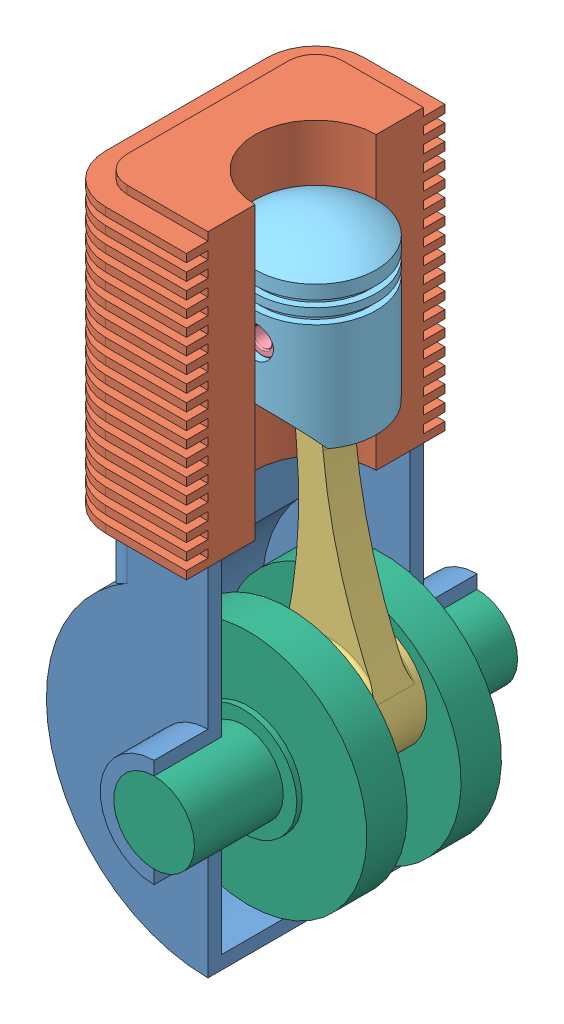
SolidWorks assembly Złożenie, configuration Default. Lengths in mm.
Overall size (122.37 241.19 120).
6 component instances, 6 part files, 12 mates.
Components (placement in the parent):
- Obudowa-1: Obudowa [Default] at (24.5213 60.7342 119.9194) size (60 132 120)
- cylinder-1: cylinder [Default] at (24.5213 132.7342 124.9194) x (0 0 -1) z (1 0 0) size (96 108 48)
- Korbowód-1: Korbowód [Default] at (35.8522 77.2148 84.9194) x (0.995532 0.094424 0) z (0 0 1) size (40 151 20)
- Sworzeń-1: Sworzeń [Default] at (24.5213 196.6787 64.9194) x (0.04525 -0.998976 0) z (0 0 1) size (12 12 40)
- Tłok-1: Tłok [60] at (24.5213 166.6787 84.9194) size (45 60 45)
- Wał-1: Wał [Default] at (24.5213 60.7342 111.9194) x (0.824032 -0.566544 0) z (0 0 1) size (88 88 120)
Mates (geometry in assembly coordinates):
- Wspólnie1: coincident anti-aligned: plane of Obudowa-1 through (-15.4787 132.7342 124.9194) normal (0 1 0); plane of cylinder-1 through (24.5213 132.7342 84.9194) normal (0 -1 0)
- Wspólnie2: coincident aligned: plane of Obudowa-1 through (24.5213 80.7342 144.9194) normal (1 0 0); plane of cylinder-1 through (24.5213 240.7342 107.4194) normal (1 0 0)
- Wspólnie3: coincident aligned: plane of Obudowa-1 through (24.5213 60.7342 44.9194) normal (0 0 -1); plane of cylinder-1 through (-15.4787 240.7342 44.9194) normal (0 0 -1)
- Koncentryczne11: concentric anti-aligned: cylinder of Sworzeń-1 through (24.5213 196.6787 104.9194) axis (0 0 -1) radius 6; cylinder of Tłok-1 through (24.5213 196.6787 62.4194) axis (0 0 1) radius 6
- Szerokość1: width anti-aligned: plane of Sworzeń-1 through (24.5213 196.6787 104.9194) normal (0 0 1); plane of Tłok-1 through (24.5213 196.6787 64.9194) normal (0 0 -1); plane of Sworzeń-1 through (24.5213 196.6787 94.9194) normal (0 0 -1); plane of Tłok-1 through (24.5213 196.6787 74.9194) normal (0 0 1)
- Koncentryczne12: concentric aligned: cylinder of Korbowód-1 through (24.5213 196.6787 94.9194) axis (0 0 -1) radius 6; cylinder of Sworzeń-1 through (24.5213 196.6787 104.9194) axis (0 0 -1) radius 6
- Wspólnie4: coincident anti-aligned: plane of Korbowód-1 through (24.5213 196.6787 94.9194) normal (0 0 1); plane of Tłok-1 through (24.5213 196.6787 94.9194) normal (0 0 -1)
- Koncentryczne13: concentric anti-aligned: cylinder of Korbowód-1 through (35.8522 77.2148 94.9194) axis (0 0 -1) radius 15; cylinder of Wał-1 through (35.8522 77.2148 84.9194) axis (0 0 1) radius 15
- Wspólnie6: coincident anti-aligned: plane of Korbowód-1 through (35.8522 77.2148 74.9194) normal (0 0 -1); plane of Wał-1 through (24.5213 60.7342 74.9194) normal (0 0 1)
- Wspólnie7: coincident aligned: plane of Obudowa-1 through (24.5213 60.7342 24.9194) normal (0 0 -1); plane of Wał-1 through (24.5213 60.7342 24.9194) normal (0 0 -1)
- Koncentryczne14: concentric aligned: cylinder of Obudowa-1 through (24.5213 60.7342 24.9194) axis (0 0 1) radius 15; cylinder of Wał-1 through (24.5213 60.7342 24.9194) axis (0 0 1) radius 15
- Koncentryczne15: concentric aligned: cylinder of cylinder-1 through (24.5213 240.7342 84.9194) axis (0 -1 0) radius 22.5; cylinder of Tłok-1 through (24.5213 166.6787 84.9194) axis (0 -1 0) radius 22.5
